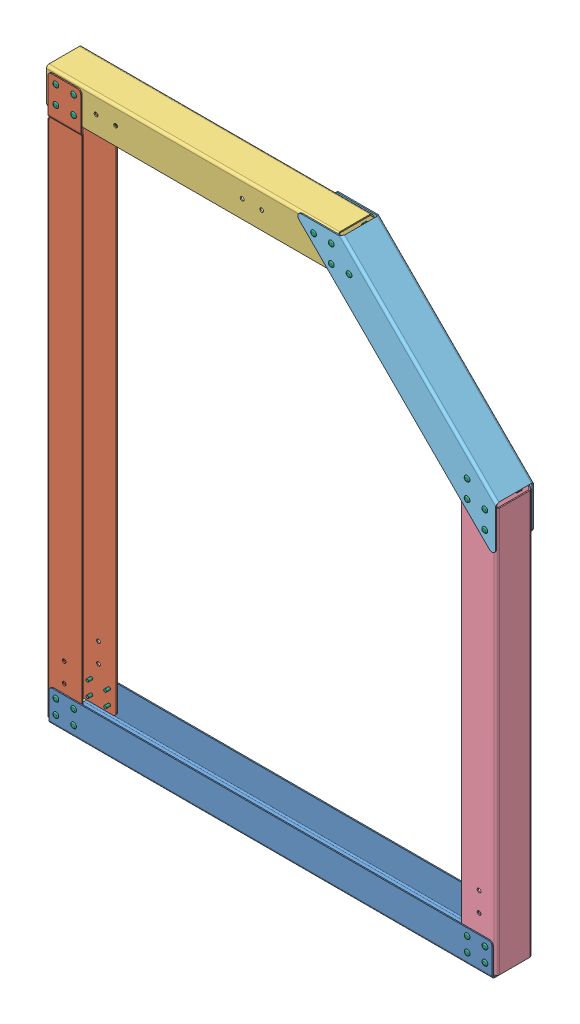
SolidWorks assembly GE-20302, configuration Default. Lengths in mm.
Overall size (844.8 1054.55 70.81).
45 component instances, 6 part files, 94 mates.
Components (placement in the parent):
- GE-20302-01-1: GE-20302-01 [Default] at origin size (793.75 57.15 67.6)
- GE-20302-02-1: GE-20302-02 [Default] at (-4.2977 4.2977 0) size (63.5 1003.3 67.6)
- GE-20302-03-1: GE-20302-03 [Default] at (-6.35 1013.9477 -63.5) size (573.17 63.5 63.5)
- GE-20302-04-1: GE-20302-04 [Default] at (800.1 4.2977 0) size (63.5 776.37 63.5)
- GE-20302-05-1: GE-20302-05 [Default] at (799.8947 737.8048 0) x (-0.707107 0.707107 0) z (0 0 1) size (495.46 63.5 67.6)
- rivet_.1875_.126-.25-1: rivet_.1875_.126-.25 [Default] at (12.7 963.1477 2.0523) size (10.01 10.01 13.03)
- rivet_.1875_.126-.25-2: rivet_.1875_.126-.25 [Default] at (12.7 994.8977 2.0523) x (0.987351 0.158553 0) z (0 0 1) size (10.01 10.01 13.03)
- rivet_.1875_.126-.25-4: rivet_.1875_.126-.25 [Default] at (44.45 994.8977 2.0523) x (0.959125 0.282984 0) z (0 0 1) size (10.01 10.01 13.03)
- rivet_.1875_.126-.25-6: rivet_.1875_.126-.25 [Default] at (44.45 963.1477 2.0523) x (0.928571 0.371154 0) z (0 0 1) size (10.01 10.01 13.03)
- rivet_.1875_.126-.25-8: rivet_.1875_.126-.25 [Default] at (12.7 994.8977 -65.5523) x (-0.906989 0.421154 0) z (0 0 -1) size (10.01 10.01 13.03)
- rivet_.1875_.126-.25-10: rivet_.1875_.126-.25 [Default] at (44.45 994.8977 -65.5523) x (-0.902849 0.429957 0) z (0 0 -1) size (10.01 10.01 13.03)
- rivet_.1875_.126-.25-12: rivet_.1875_.126-.25 [Default] at (44.45 963.1477 -65.5523) x (-0.919615 0.39282 0) z (0 0 -1) size (10.01 10.01 13.03)
- rivet_.1875_.126-.25-14: rivet_.1875_.126-.25 [Default] at (12.7 963.1477 -65.5523) x (-0.952324 0.305088 0) z (0 0 -1) size (10.01 10.01 13.03)
- rivet_.1875_.126-.25-16: rivet_.1875_.126-.25 [Default] at (12.7 42.3977 -65.5523) x (-0.985697 0.168526 0) z (0 0 -1) size (10.01 10.01 13.03)
- rivet_.1875_.126-.25-18: rivet_.1875_.126-.25 [Default] at (44.45 42.3977 -65.5523) x (-1 0 0) z (0 0 -1) size (10.01 10.01 13.03)
- rivet_.1875_.126-.25-20: rivet_.1875_.126-.25 [Default] at (12.7 16.9977 -65.5523) x (-0.985697 -0.168526 0) z (0 0 -1) size (10.01 10.01 13.03)
- rivet_.1875_.126-.25-22: rivet_.1875_.126-.25 [Default] at (44.45 16.9977 -65.5523) x (-0.952324 -0.305088 0) z (0 0 -1) size (10.01 10.01 13.03)
- rivet_.1875_.126-.25-24: rivet_.1875_.126-.25 [Default] at (749.3 16.9977 -65.5523) x (-0.919615 -0.39282 0) z (0 0 -1) size (10.01 10.01 13.03)
- rivet_.1875_.126-.25-26: rivet_.1875_.126-.25 [Default] at (781.05 16.9977 -65.5523) x (-0.902849 -0.429957 0) z (0 0 -1) size (10.01 10.01 13.03)
- rivet_.1875_.126-.25-28: rivet_.1875_.126-.25 [Default] at (781.05 42.3977 -65.5523) x (-0.906989 -0.421154 0) z (0 0 -1) size (10.01 10.01 13.03)
- rivet_.1875_.126-.25-30: rivet_.1875_.126-.25 [Default] at (749.3 42.3977 -65.5523) x (-0.928571 -0.371154 0) z (0 0 -1) size (10.01 10.01 13.03)
- rivet_.1875_.126-.25-32: rivet_.1875_.126-.25 [Default] at (781.05 42.3977 2.0523) x (0.959125 -0.282984 0) z (0 0 1) size (10.01 10.01 13.03)
- rivet_.1875_.126-.25-34: rivet_.1875_.126-.25 [Default] at (781.05 16.9977 2.0523) x (0.987351 -0.158553 0) z (0 0 1) size (10.01 10.01 13.03)
- rivet_.1875_.126-.25-36: rivet_.1875_.126-.25 [Default] at (749.3 42.3977 2.0523) size (10.01 10.01 13.03)
- rivet_.1875_.126-.25-38: rivet_.1875_.126-.25 [Default] at (749.3 16.9977 2.0523) x (0.982034 0.188703 0) z (0 0 1) size (10.01 10.01 13.03)
- rivet_.1875_.126-.25-40: rivet_.1875_.126-.25 [Default] at (12.7 42.3977 2.0523) x (0.916631 0.399735 0) z (0 0 1) size (10.01 10.01 13.03)
- rivet_.1875_.126-.25-42: rivet_.1875_.126-.25 [Default] at (12.7 16.9977 2.0523) x (0.785714 0.61859 0) z (0 0 1) size (10.01 10.01 13.03)
- rivet_.1875_.126-.25-44: rivet_.1875_.126-.25 [Default] at (44.45 42.3977 2.0523) x (0.572252 0.820078 0) z (0 0 1) size (10.01 10.01 13.03)
- rivet_.1875_.126-.25-46: rivet_.1875_.126-.25 [Default] at (44.45 16.9977 2.0523) x (0.266647 0.963794 0) z (0 0 1) size (10.01 10.01 13.03)
- rivet_.1875_.126-.25-48: rivet_.1875_.126-.25 [Default] at (474.1977 994.8977 2.0523) x (0.987351 0.158553 0) z (0 0 1) size (10.01 10.01 13.03)
- rivet_.1875_.126-.25-50: rivet_.1875_.126-.25 [Default] at (505.9477 994.8977 2.0523) x (0.959125 0.282984 0) z (0 0 1) size (10.01 10.01 13.03)
- rivet_.1875_.126-.25-52: rivet_.1875_.126-.25 [Default] at (505.9477 963.1477 2.0523) x (0.928571 0.371154 0) z (0 0 1) size (10.01 10.01 13.03)
- rivet_.1875_.126-.25-54: rivet_.1875_.126-.25 [Default] at (537.6977 963.1477 2.0523) x (0.906989 0.421154 0) z (0 0 1) size (10.01 10.01 13.03)
- rivet_.1875_.126-.25-56: rivet_.1875_.126-.25 [Default] at (505.9477 963.1477 -65.5523) x (-0.902849 0.429957 0) z (0 0 -1) size (10.01 10.01 13.03)
- rivet_.1875_.126-.25-58: rivet_.1875_.126-.25 [Default] at (505.9477 994.8977 -65.5523) x (-0.919615 0.39282 0) z (0 0 -1) size (10.01 10.01 13.03)
- rivet_.1875_.126-.25-60: rivet_.1875_.126-.25 [Default] at (474.1977 994.8977 -65.5523) x (-0.952324 0.305088 0) z (0 0 -1) size (10.01 10.01 13.03)
- rivet_.1875_.126-.25-62: rivet_.1875_.126-.25 [Default] at (537.6977 963.1477 -65.5523) x (-0.985697 0.168526 0) z (0 0 -1) size (10.01 10.01 13.03)
- rivet_.1875_.126-.25-64: rivet_.1875_.126-.25 [Default] at (749.0947 751.7507 2.0523) x (0.987351 0.158553 0) z (0 0 1) size (10.01 10.01 13.03)
- rivet_.1875_.126-.25-66: rivet_.1875_.126-.25 [Default] at (749.0947 720.0007 2.0523) x (0.959125 0.282984 0) z (0 0 1) size (10.01 10.01 13.03)
- rivet_.1875_.126-.25-68: rivet_.1875_.126-.25 [Default] at (780.8447 720.0007 2.0523) x (0.928571 0.371154 0) z (0 0 1) size (10.01 10.01 13.03)
- rivet_.1875_.126-.25-70: rivet_.1875_.126-.25 [Default] at (780.8447 688.2507 2.0523) x (0.906989 0.421154 0) z (0 0 1) size (10.01 10.01 13.03)
- rivet_.1875_.126-.25-72: rivet_.1875_.126-.25 [Default] at (749.0947 751.7507 -65.5523) x (-0.902849 0.429957 0) z (0 0 -1) size (10.01 10.01 13.03)
- rivet_.1875_.126-.25-74: rivet_.1875_.126-.25 [Default] at (749.0947 720.0007 -65.5523) x (-0.919615 0.39282 0) z (0 0 -1) size (10.01 10.01 13.03)
- rivet_.1875_.126-.25-76: rivet_.1875_.126-.25 [Default] at (780.8447 720.0007 -65.5523) x (-0.952324 0.305088 0) z (0 0 -1) size (10.01 10.01 13.03)
- rivet_.1875_.126-.25-78: rivet_.1875_.126-.25 [Default] at (780.8447 688.2507 -65.5523) x (-0.985697 0.168526 0) z (0 0 -1) size (10.01 10.01 13.03)
Mates (geometry in assembly coordinates):
- Coincident1: coincident aligned: circle of tallVertical-1; circle of bottom-1
- Concentric1: concentric aligned: cylinder of GE-20302-01-1 through (12.7 42.3977 2.0523) axis (0 0 1) radius 2.4574; cylinder of GE-20302-02-1 through (12.7 42.3977 2.0523) axis (0 0 1) radius 2.4574
- Concentric2: concentric aligned: cylinder of tallVertical-1 through (44.45 994.8977 2.0523) axis (0 0 1) radius 2.4574; cylinder of GE-20302-03-1 through (44.45 994.8977 0) axis (0 0 1) radius 2.4574
- Coincident3: coincident anti-aligned: circle of bottom-1; circle of shortVertical-1
- Concentric3: concentric aligned: cylinder of GE-20302-01-1 through (749.3 42.3977 2.0523) axis (0 0 1) radius 2.4574; cylinder of GE-20302-04-1 through (749.3 42.3977 0) axis (0 0 1) radius 2.4574
- Coincident5: coincident aligned: plane of GE-20302-02-1 through (-6.35 4.2977 0) normal (-1 0 0); plane of sideFrame-1/sideFrame_2-1 through (-6.35 969.5561 -225.0865) normal (-1 0 0)
- Coincident6: coincident aligned: plane of GE-20302-01-1 through (0 -2.0523 0) normal (0 -1 0); plane of sideFrame-1/sideFrame_1-1 through (38.1 -1.9939 -225.0865) normal (0 -1 0)
- Coincident7: coincident anti-aligned: circle of tallVertical-1; circle of top-1
- Coincident8: coincident anti-aligned: plane of GE-20302-04-1 through (800.1 4.2977 -63.5) normal (0 0 -1); plane of GE-20302-05-1 through (799.8947 737.8048 -63.5) normal (0 0 1)
- Coincident9: coincident: plane of shortVertical-1 through (797.56 708.66 -63.5) normal (0.707107 0.707107 0); line of diagonal-1 through (500.2497 1005.9703 -63.5) axis (0.707107 -0.707107 0)
- Coincident10: coincident: line of shortVertical-1 through (791.21 715.01 0) axis (0 -1 0); plane of diagonal-1
- Coincident12: coincident aligned: plane of shortVertical-1 through (800.1 3.81 0) normal (1 0 0); plane of diagonal-1
- Concentric6: concentric aligned: cylinder of GE-20302-03-1 through (505.9477 994.8977 0) axis (0 0 1) radius 2.4574; cylinder of GE-20302-05-1 through (505.9477 994.8977 2.0523) axis (0 0 1) radius 2.4574
- Concentric7: concentric aligned: cylinder of GE-20302-03-1 through (474.1977 994.8977 0) axis (0 0 1) radius 2.4574; cylinder of GE-20302-05-1 through (474.1977 994.8977 2.0523) axis (0 0 1) radius 2.4574
- Concentric8: concentric aligned: cylinder of GE-20302-02-1 through (12.7 963.1477 2.0523) axis (0 0 1) radius 2.4574; cylinder of rivet_.1875_.126-.25-1 through (12.7 963.1477 -9.3777) axis (0 0 1) radius 2.3813
- Coincident13: coincident anti-aligned: plane of GE-20302-02-1 through (-4.2977 3.7125 2.0523) normal (0 0 1); plane of rivet_.1875_.126-.25-1 through (12.7 963.1477 2.0523) normal (0 0 -1)
- Concentric9: concentric aligned: cylinder of GE-20302-02-1 through (12.7 994.8977 2.0523) axis (0 0 1) radius 2.4574; cylinder of rivet_.1875_.126-.25-2 through (12.7 994.8977 -9.3777) axis (0 0 1) radius 2.3813
- Coincident14: coincident anti-aligned: plane of GE-20302-02-1 through (-4.2977 3.7125 2.0523) normal (0 0 1); plane of rivet_.1875_.126-.25-2 through (12.7 994.8977 2.0523) normal (0 0 -1)
- Concentric10: concentric aligned: cylinder of GE-20302-02-1 through (44.45 994.8977 2.0523) axis (0 0 1) radius 2.4574; cylinder of rivet_.1875_.126-.25-4 through (44.45 994.8977 -9.3777) axis (0 0 1) radius 2.3813
- Coincident15: coincident anti-aligned: plane of GE-20302-02-1 through (-4.2977 3.7125 2.0523) normal (0 0 1); plane of rivet_.1875_.126-.25-4 through (44.45 994.8977 2.0523) normal (0 0 -1)
- Concentric11: concentric aligned: cylinder of GE-20302-02-1 through (44.45 963.1477 2.0523) axis (0 0 1) radius 2.4574; cylinder of rivet_.1875_.126-.25-6 through (44.45 963.1477 -9.3777) axis (0 0 1) radius 2.3813
- Coincident16: coincident anti-aligned: plane of GE-20302-02-1 through (-4.2977 3.7125 2.0523) normal (0 0 1); plane of rivet_.1875_.126-.25-6 through (44.45 963.1477 2.0523) normal (0 0 -1)
- Concentric12: concentric anti-aligned: cylinder of GE-20302-02-1 through (12.7 994.8977 2.0523) axis (0 0 1) radius 2.4574; cylinder of rivet_.1875_.126-.25-8 through (12.7 994.8977 -54.1223) axis (0 0 -1) radius 2.3813
- Coincident17: coincident anti-aligned: plane of GE-20302-02-1 through (-4.2977 3.7125 -65.5523) normal (0 0 -1); plane of rivet_.1875_.126-.25-8 through (12.7 994.8977 -65.5523) normal (0 0 1)
- Concentric13: concentric anti-aligned: cylinder of GE-20302-02-1 through (44.45 994.8977 2.0523) axis (0 0 1) radius 2.4574; cylinder of rivet_.1875_.126-.25-10 through (44.45 994.8977 -54.1223) axis (0 0 -1) radius 2.3813
- Coincident18: coincident anti-aligned: plane of GE-20302-02-1 through (-4.2977 3.7125 -65.5523) normal (0 0 -1); plane of rivet_.1875_.126-.25-10 through (44.45 994.8977 -65.5523) normal (0 0 1)
- Concentric14: concentric anti-aligned: cylinder of GE-20302-02-1 through (44.45 963.1477 2.0523) axis (0 0 1) radius 2.4574; cylinder of rivet_.1875_.126-.25-12 through (44.45 963.1477 -54.1223) axis (0 0 -1) radius 2.3813
- Coincident19: coincident anti-aligned: plane of GE-20302-02-1 through (-4.2977 3.7125 -65.5523) normal (0 0 -1); plane of rivet_.1875_.126-.25-12 through (44.45 963.1477 -65.5523) normal (0 0 1)
- Concentric15: concentric anti-aligned: cylinder of GE-20302-02-1 through (12.7 963.1477 2.0523) axis (0 0 1) radius 2.4574; cylinder of rivet_.1875_.126-.25-14 through (12.7 963.1477 -54.1223) axis (0 0 -1) radius 2.3813
- Coincident20: coincident anti-aligned: plane of GE-20302-02-1 through (-4.2977 3.7125 -65.5523) normal (0 0 -1); plane of rivet_.1875_.126-.25-14 through (12.7 963.1477 -65.5523) normal (0 0 1)
- Concentric16: concentric anti-aligned: cylinder of GE-20302-01-1 through (12.7 42.3977 2.0523) axis (0 0 1) radius 2.4574; cylinder of rivet_.1875_.126-.25-16 through (12.7 42.3977 -54.1223) axis (0 0 -1) radius 2.3813
- Coincident21: coincident anti-aligned: plane of GE-20302-01-1 through (0 0 -65.5523) normal (0 0 -1); plane of rivet_.1875_.126-.25-16 through (12.7 42.3977 -65.5523) normal (0 0 1)
- Concentric17: concentric anti-aligned: cylinder of GE-20302-01-1 through (44.45 42.3977 2.0523) axis (0 0 1) radius 2.4574; cylinder of rivet_.1875_.126-.25-18 through (44.45 42.3977 -54.1223) axis (0 0 -1) radius 2.3813
- Coincident22: coincident anti-aligned: plane of GE-20302-01-1 through (0 0 -65.5523) normal (0 0 -1); plane of rivet_.1875_.126-.25-18 through (44.45 42.3977 -65.5523) normal (0 0 1)
- Concentric18: concentric anti-aligned: cylinder of GE-20302-01-1 through (12.7 16.9977 2.0523) axis (0 0 1) radius 2.4574; cylinder of rivet_.1875_.126-.25-20 through (12.7 16.9977 -54.1223) axis (0 0 -1) radius 2.3813
- Coincident23: coincident anti-aligned: plane of GE-20302-01-1 through (0 0 -65.5523) normal (0 0 -1); plane of rivet_.1875_.126-.25-20 through (12.7 16.9977 -65.5523) normal (0 0 1)
- Concentric19: concentric anti-aligned: cylinder of GE-20302-01-1 through (44.45 16.9977 2.0523) axis (0 0 1) radius 2.4574; cylinder of rivet_.1875_.126-.25-22 through (44.45 16.9977 -54.1223) axis (0 0 -1) radius 2.3813
- Coincident24: coincident anti-aligned: plane of GE-20302-01-1 through (0 0 -65.5523) normal (0 0 -1); plane of rivet_.1875_.126-.25-22 through (44.45 16.9977 -65.5523) normal (0 0 1)
- Concentric20: concentric anti-aligned: cylinder of GE-20302-01-1 through (749.3 16.9977 2.0523) axis (0 0 1) radius 2.4574; cylinder of rivet_.1875_.126-.25-24 through (749.3 16.9977 -54.1223) axis (0 0 -1) radius 2.3813
- Coincident25: coincident anti-aligned: plane of GE-20302-01-1 through (0 0 -65.5523) normal (0 0 -1); plane of rivet_.1875_.126-.25-24 through (749.3 16.9977 -65.5523) normal (0 0 1)
- Concentric21: concentric anti-aligned: cylinder of GE-20302-01-1 through (781.05 16.9977 2.0523) axis (0 0 1) radius 2.4574; cylinder of rivet_.1875_.126-.25-26 through (781.05 16.9977 -54.1223) axis (0 0 -1) radius 2.3813
- Coincident26: coincident anti-aligned: plane of GE-20302-01-1 through (0 0 -65.5523) normal (0 0 -1); plane of rivet_.1875_.126-.25-26 through (781.05 16.9977 -65.5523) normal (0 0 1)
- Concentric22: concentric anti-aligned: cylinder of GE-20302-01-1 through (781.05 42.3977 2.0523) axis (0 0 1) radius 2.4574; cylinder of rivet_.1875_.126-.25-28 through (781.05 42.3977 -54.1223) axis (0 0 -1) radius 2.3813
- Coincident27: coincident anti-aligned: plane of GE-20302-01-1 through (0 0 -65.5523) normal (0 0 -1); plane of rivet_.1875_.126-.25-28 through (781.05 42.3977 -65.5523) normal (0 0 1)
- Concentric23: concentric anti-aligned: cylinder of GE-20302-01-1 through (749.3 42.3977 2.0523) axis (0 0 1) radius 2.4574; cylinder of rivet_.1875_.126-.25-30 through (749.3 42.3977 -54.1223) axis (0 0 -1) radius 2.3813
- Coincident28: coincident anti-aligned: plane of GE-20302-01-1 through (0 0 -65.5523) normal (0 0 -1); plane of rivet_.1875_.126-.25-30 through (749.3 42.3977 -65.5523) normal (0 0 1)
- Concentric24: concentric aligned: cylinder of GE-20302-01-1 through (781.05 42.3977 2.0523) axis (0 0 1) radius 2.4574; cylinder of rivet_.1875_.126-.25-32 through (781.05 42.3977 -9.3777) axis (0 0 1) radius 2.3813
- Coincident29: coincident anti-aligned: plane of GE-20302-01-1 through (0 0 2.0523) normal (0 0 1); plane of rivet_.1875_.126-.25-32 through (781.05 42.3977 2.0523) normal (0 0 -1)
- Concentric25: concentric aligned: cylinder of GE-20302-01-1 through (781.05 16.9977 2.0523) axis (0 0 1) radius 2.4574; cylinder of rivet_.1875_.126-.25-34 through (781.05 16.9977 -9.3777) axis (0 0 1) radius 2.3813
- Coincident30: coincident anti-aligned: plane of GE-20302-01-1 through (0 0 2.0523) normal (0 0 1); plane of rivet_.1875_.126-.25-34 through (781.05 16.9977 2.0523) normal (0 0 -1)
- Concentric26: concentric aligned: cylinder of GE-20302-01-1 through (749.3 42.3977 2.0523) axis (0 0 1) radius 2.4574; cylinder of rivet_.1875_.126-.25-36 through (749.3 42.3977 -9.3777) axis (0 0 1) radius 2.3813
- Coincident31: coincident anti-aligned: plane of GE-20302-01-1 through (0 0 2.0523) normal (0 0 1); plane of rivet_.1875_.126-.25-36 through (749.3 42.3977 2.0523) normal (0 0 -1)
- Concentric27: concentric aligned: cylinder of GE-20302-01-1 through (749.3 16.9977 2.0523) axis (0 0 1) radius 2.4574; cylinder of rivet_.1875_.126-.25-38 through (749.3 16.9977 -9.3777) axis (0 0 1) radius 2.3813
- Coincident32: coincident anti-aligned: plane of GE-20302-01-1 through (0 0 2.0523) normal (0 0 1); plane of rivet_.1875_.126-.25-38 through (749.3 16.9977 2.0523) normal (0 0 -1)
- Concentric28: concentric aligned: cylinder of GE-20302-01-1 through (12.7 42.3977 2.0523) axis (0 0 1) radius 2.4574; cylinder of rivet_.1875_.126-.25-40 through (12.7 42.3977 -9.3777) axis (0 0 1) radius 2.3813
- Coincident33: coincident anti-aligned: plane of GE-20302-01-1 through (0 0 2.0523) normal (0 0 1); plane of rivet_.1875_.126-.25-40 through (12.7 42.3977 2.0523) normal (0 0 -1)
- Concentric29: concentric aligned: cylinder of GE-20302-01-1 through (12.7 16.9977 2.0523) axis (0 0 1) radius 2.4574; cylinder of rivet_.1875_.126-.25-42 through (12.7 16.9977 -9.3777) axis (0 0 1) radius 2.3813
- Coincident34: coincident anti-aligned: plane of GE-20302-01-1 through (0 0 2.0523) normal (0 0 1); plane of rivet_.1875_.126-.25-42 through (12.7 16.9977 2.0523) normal (0 0 -1)
- Concentric30: concentric aligned: cylinder of GE-20302-01-1 through (44.45 42.3977 2.0523) axis (0 0 1) radius 2.4574; cylinder of rivet_.1875_.126-.25-44 through (44.45 42.3977 -9.3777) axis (0 0 1) radius 2.3813
- Coincident35: coincident anti-aligned: plane of GE-20302-01-1 through (0 0 2.0523) normal (0 0 1); plane of rivet_.1875_.126-.25-44 through (44.45 42.3977 2.0523) normal (0 0 -1)
- Concentric31: concentric aligned: cylinder of GE-20302-01-1 through (44.45 16.9977 2.0523) axis (0 0 1) radius 2.4574; cylinder of rivet_.1875_.126-.25-46 through (44.45 16.9977 -9.3777) axis (0 0 1) radius 2.3813
- Coincident36: coincident anti-aligned: plane of GE-20302-01-1 through (0 0 2.0523) normal (0 0 1); plane of rivet_.1875_.126-.25-46 through (44.45 16.9977 2.0523) normal (0 0 -1)
- Concentric32: concentric aligned: cylinder of GE-20302-05-1 through (474.1977 994.8977 2.0523) axis (0 0 1) radius 2.4574; cylinder of rivet_.1875_.126-.25-48 through (474.1977 994.8977 -9.3777) axis (0 0 1) radius 2.3813
- Coincident37: coincident anti-aligned: plane of GE-20302-05-1 through (799.8947 737.8048 2.0523) normal (0 0 1); plane of rivet_.1875_.126-.25-48 through (474.1977 994.8977 2.0523) normal (0 0 -1)
- Concentric33: concentric aligned: cylinder of GE-20302-05-1 through (505.9477 994.8977 2.0523) axis (0 0 1) radius 2.4574; cylinder of rivet_.1875_.126-.25-50 through (505.9477 994.8977 -9.3777) axis (0 0 1) radius 2.3813
- Coincident38: coincident anti-aligned: plane of GE-20302-05-1 through (799.8947 737.8048 2.0523) normal (0 0 1); plane of rivet_.1875_.126-.25-50 through (505.9477 994.8977 2.0523) normal (0 0 -1)
- Concentric34: concentric aligned: cylinder of GE-20302-05-1 through (505.9477 963.1477 2.0523) axis (0 0 1) radius 2.4574; cylinder of rivet_.1875_.126-.25-52 through (505.9477 963.1477 -9.3777) axis (0 0 1) radius 2.3813
- Coincident39: coincident anti-aligned: plane of GE-20302-05-1 through (799.8947 737.8048 2.0523) normal (0 0 1); plane of rivet_.1875_.126-.25-52 through (505.9477 963.1477 2.0523) normal (0 0 -1)
- Concentric35: concentric aligned: cylinder of GE-20302-05-1 through (537.6977 963.1477 2.0523) axis (0 0 1) radius 2.4574; cylinder of rivet_.1875_.126-.25-54 through (537.6977 963.1477 -9.3777) axis (0 0 1) radius 2.3813
- Coincident40: coincident anti-aligned: plane of GE-20302-05-1 through (799.8947 737.8048 2.0523) normal (0 0 1); plane of rivet_.1875_.126-.25-54 through (537.6977 963.1477 2.0523) normal (0 0 -1)
- Concentric36: concentric anti-aligned: cylinder of GE-20302-05-1 through (505.9477 963.1477 2.0523) axis (0 0 1) radius 2.4574; cylinder of rivet_.1875_.126-.25-56 through (505.9477 963.1477 -54.1223) axis (0 0 -1) radius 2.3813
- Coincident41: coincident anti-aligned: plane of GE-20302-05-1 through (799.8947 737.8048 -65.5523) normal (0 0 -1); plane of rivet_.1875_.126-.25-56 through (505.9477 963.1477 -65.5523) normal (0 0 1)
- Concentric37: concentric anti-aligned: cylinder of GE-20302-05-1 through (505.9477 994.8977 2.0523) axis (0 0 1) radius 2.4574; cylinder of rivet_.1875_.126-.25-58 through (505.9477 994.8977 -54.1223) axis (0 0 -1) radius 2.3813
- Coincident42: coincident anti-aligned: plane of GE-20302-05-1 through (799.8947 737.8048 -65.5523) normal (0 0 -1); plane of rivet_.1875_.126-.25-58 through (505.9477 994.8977 -65.5523) normal (0 0 1)
- Concentric38: concentric anti-aligned: cylinder of GE-20302-05-1 through (474.1977 994.8977 2.0523) axis (0 0 1) radius 2.4574; cylinder of rivet_.1875_.126-.25-60 through (474.1977 994.8977 -54.1223) axis (0 0 -1) radius 2.3813
- Coincident43: coincident anti-aligned: plane of GE-20302-05-1 through (799.8947 737.8048 -65.5523) normal (0 0 -1); plane of rivet_.1875_.126-.25-60 through (474.1977 994.8977 -65.5523) normal (0 0 1)
- Concentric39: concentric anti-aligned: cylinder of GE-20302-05-1 through (537.6977 963.1477 2.0523) axis (0 0 1) radius 2.4574; cylinder of rivet_.1875_.126-.25-62 through (537.6977 963.1477 -54.1223) axis (0 0 -1) radius 2.3813
- Coincident44: coincident anti-aligned: plane of GE-20302-05-1 through (799.8947 737.8048 -65.5523) normal (0 0 -1); plane of rivet_.1875_.126-.25-62 through (537.6977 963.1477 -65.5523) normal (0 0 1)
- Concentric40: concentric aligned: cylinder of GE-20302-05-1 through (749.0947 751.7507 2.0523) axis (0 0 1) radius 2.4574; cylinder of rivet_.1875_.126-.25-64 through (749.0947 751.7507 -9.3777) axis (0 0 1) radius 2.3813
- Coincident45: coincident anti-aligned: plane of GE-20302-05-1 through (799.8947 737.8048 2.0523) normal (0 0 1); plane of rivet_.1875_.126-.25-64 through (749.0947 751.7507 2.0523) normal (0 0 -1)
- Concentric41: concentric aligned: cylinder of GE-20302-05-1 through (749.0947 720.0007 2.0523) axis (0 0 1) radius 2.4574; cylinder of rivet_.1875_.126-.25-66 through (749.0947 720.0007 -9.3777) axis (0 0 1) radius 2.3813
- Coincident46: coincident anti-aligned: plane of GE-20302-05-1 through (799.8947 737.8048 2.0523) normal (0 0 1); plane of rivet_.1875_.126-.25-66 through (749.0947 720.0007 2.0523) normal (0 0 -1)
- Concentric42: concentric aligned: cylinder of GE-20302-05-1 through (780.8447 720.0007 2.0523) axis (0 0 1) radius 2.4574; cylinder of rivet_.1875_.126-.25-68 through (780.8447 720.0007 -9.3777) axis (0 0 1) radius 2.3813
- Coincident47: coincident anti-aligned: plane of GE-20302-05-1 through (799.8947 737.8048 2.0523) normal (0 0 1); plane of rivet_.1875_.126-.25-68 through (780.8447 720.0007 2.0523) normal (0 0 -1)
- Concentric43: concentric aligned: cylinder of GE-20302-05-1 through (780.8447 688.2507 2.0523) axis (0 0 1) radius 2.4574; cylinder of rivet_.1875_.126-.25-70 through (780.8447 688.2507 -9.3777) axis (0 0 1) radius 2.3813
- Coincident48: coincident anti-aligned: plane of GE-20302-05-1 through (799.8947 737.8048 2.0523) normal (0 0 1); plane of rivet_.1875_.126-.25-70 through (780.8447 688.2507 2.0523) normal (0 0 -1)
- Concentric44: concentric anti-aligned: cylinder of GE-20302-05-1 through (749.0947 751.7507 2.0523) axis (0 0 1) radius 2.4574; cylinder of rivet_.1875_.126-.25-72 through (749.0947 751.7507 -54.1223) axis (0 0 -1) radius 2.3813
- Coincident49: coincident anti-aligned: plane of GE-20302-05-1 through (799.8947 737.8048 -65.5523) normal (0 0 -1); plane of rivet_.1875_.126-.25-72 through (749.0947 751.7507 -65.5523) normal (0 0 1)
- Concentric45: concentric anti-aligned: cylinder of GE-20302-05-1 through (749.0947 720.0007 2.0523) axis (0 0 1) radius 2.4574; cylinder of rivet_.1875_.126-.25-74 through (749.0947 720.0007 -54.1223) axis (0 0 -1) radius 2.3813
- Coincident50: coincident anti-aligned: plane of GE-20302-05-1 through (799.8947 737.8048 -65.5523) normal (0 0 -1); plane of rivet_.1875_.126-.25-74 through (749.0947 720.0007 -65.5523) normal (0 0 1)
- Concentric46: concentric anti-aligned: cylinder of GE-20302-05-1 through (780.8447 720.0007 2.0523) axis (0 0 1) radius 2.4574; cylinder of rivet_.1875_.126-.25-76 through (780.8447 720.0007 -54.1223) axis (0 0 -1) radius 2.3813
- Coincident51: coincident anti-aligned: plane of GE-20302-05-1 through (799.8947 737.8048 -65.5523) normal (0 0 -1); plane of rivet_.1875_.126-.25-76 through (780.8447 720.0007 -65.5523) normal (0 0 1)
- Concentric47: concentric anti-aligned: cylinder of GE-20302-05-1 through (780.8447 688.2507 2.0523) axis (0 0 1) radius 2.4574; cylinder of rivet_.1875_.126-.25-78 through (780.8447 688.2507 -54.1223) axis (0 0 -1) radius 2.3813
- Coincident52: coincident anti-aligned: plane of GE-20302-05-1 through (799.8947 737.8048 -65.5523) normal (0 0 -1); plane of rivet_.1875_.126-.25-78 through (780.8447 688.2507 -65.5523) normal (0 0 1)
